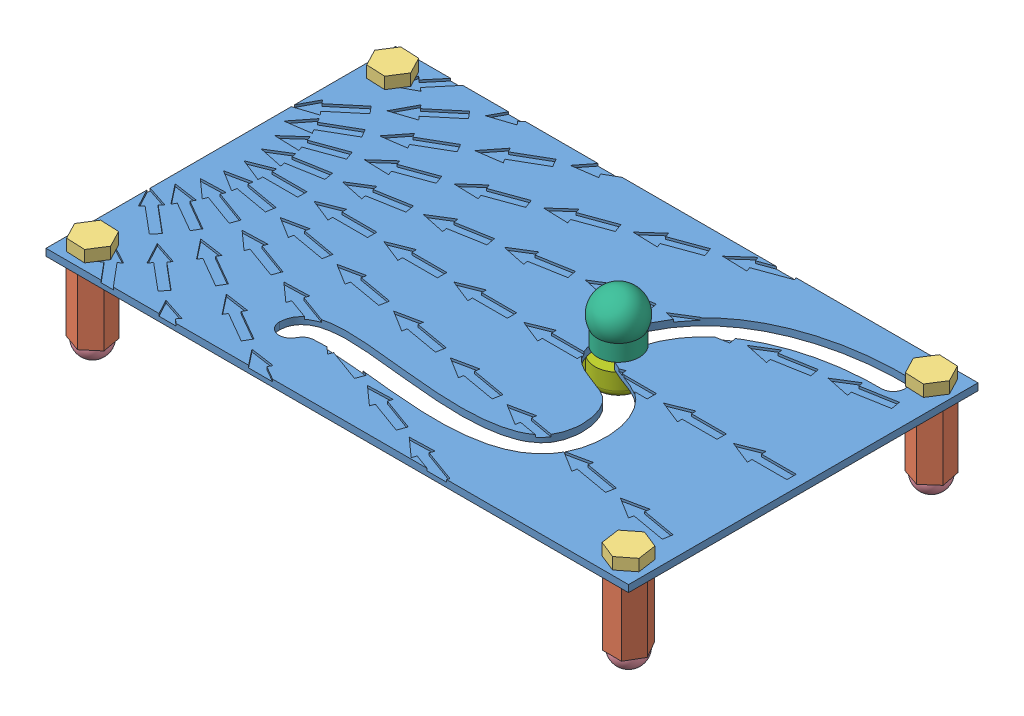
SolidWorks assembly line integral model 2, configuration Default. Lengths in mm.
Overall size (251.5 61.65 151.31).
16 component instances, 7 part files, 31 mates.
Components (placement in the parent):
- base3 - Copy-1: base3 - Copy [Default] at (17.0516 136.2086 235.579) size (250 3 150)
- washer-1: washer [Default] at (27.0516 106.2086 225.579) x (0.759078 0 -0.650999) z (0.650999 0 0.759078) size (16.17 30.96 14.03)
- washer-2: washer [Default] at (27.0516 106.2086 96.7735) size (16.17 30.96 14.03)
- washer-3: washer [Default] at (257.0516 106.2086 95.579) x (-0.748094 0 0.663593) z (-0.663593 0 -0.748094) size (16.17 30.96 14.03)
- washer-4: washer [Default] at (257.0516 106.2086 225.579) size (16.17 30.96 14.03)
- bolt-1: bolt [Default] at (27.0516 109.2086 96.7735) size (16.15 35.68 14.34)
- bolt-2: bolt [Default] at (27.0516 109.2086 225.579) size (16.15 35.68 14.34)
- bolt-3: bolt [Default] at (257.0516 109.2086 225.579) x (0.758823 0 -0.651297) z (0.651297 0 0.758823) size (16.15 35.68 14.34)
- bolt-4: bolt [Default] at (257.0516 109.2086 95.579) size (16.15 35.68 14.34)
- feet-1: feet [Default] at (257.0516 106.2086 95.579) x (-0.837169 0 -0.546944) z (-0.546944 0 0.837169) size (14 12.25 14)
- feet-2: feet [Default] at (27.0516 106.2086 225.579) x (-0.837169 0 -0.546944) z (-0.546944 0 0.837169) size (14 12.25 14)
- feet-3: feet [Default] at (27.0516 106.2086 96.7735) x (-0.837169 0 -0.546944) z (-0.546944 0 0.837169) size (14 12.25 14)
- feet-4: feet [Default] at (257.0516 106.2086 225.579) x (-0.837169 0 -0.546944) z (-0.546944 0 0.837169) size (14 12.25 14)
- band holder-1: band holder [Default] at (27.0516 126.2086 165.579) x (0 0 -1) z (1 0 0) size (10 10 10)
- slider - Copy-1: slider - Copy [Default] at (175.9335 127.2086 148.7713) x (-0.925693 0 -0.378276) z (0.378276 0 -0.925693) size (20.18 33.65 20.18)
- washer clip - Copy-1: washer clip - Copy [Default] at (175.9335 136.2086 148.7713) x (0.995786 0 -0.09171) z (-0.09171 0 -0.995786) size (29 10.27 20)
Mates (geometry in assembly coordinates):
- Coincident1: coincident anti-aligned: plane of base3 - Copy-1 through (17.0516 136.2086 235.579) normal (0 -1 0); plane of washer-1 through (27.0516 136.2086 225.579) normal (0 1 0)
- Coincident2: coincident anti-aligned: plane of base3 - Copy-1 through (17.0516 139.2086 235.579) normal (0 1 0); plane of bolt-2 through (27.0516 139.2086 225.579) normal (0 -1 0)
- Concentric1: concentric anti-aligned: cylinder of washer-1 through (27.0516 106.2086 225.579) axis (0 1 0) radius 5; cylinder of bolt-2 through (27.0516 139.2086 225.579) axis (0 -1 0) radius 5
- Concentric2: concentric anti-aligned: cylinder of base3 - Copy-1 through (27.0516 129.2086 225.579) axis (0 1 0) radius 1.5; cylinder of bolt-2 through (27.0516 139.2086 225.579) axis (0 -1 0) radius 5
- Coincident3: coincident anti-aligned: plane of base3 - Copy-1 through (17.0516 136.2086 235.579) normal (0 -1 0); plane of washer-2 through (27.0516 136.2086 96.7735) normal (0 1 0)
- Concentric3: concentric anti-aligned: cylinder of base3 - Copy-1 through (27.0516 129.2086 96.7735) axis (0 1 0) radius 1.5; cylinder of bolt-1 through (27.0516 139.2086 96.7735) axis (0 -1 0) radius 5
- Concentric4: concentric anti-aligned: cylinder of washer-2 through (27.0516 106.2086 96.7735) axis (0 1 0) radius 5; cylinder of bolt-1 through (27.0516 139.2086 96.7735) axis (0 -1 0) radius 5
- Coincident4: coincident anti-aligned: plane of base3 - Copy-1 through (17.0516 139.2086 235.579) normal (0 1 0); plane of bolt-1 through (27.0516 139.2086 96.7735) normal (0 -1 0)
- Coincident5: coincident anti-aligned: plane of base3 - Copy-1 through (17.0516 136.2086 235.579) normal (0 -1 0); plane of washer-4 through (257.0516 136.2086 225.579) normal (0 1 0)
- Concentric5: concentric anti-aligned: cylinder of base3 - Copy-1 through (257.0516 129.2086 225.579) axis (0 1 0) radius 1.5; cylinder of bolt-3 through (257.0516 139.2086 225.579) axis (0 -1 0) radius 5
- Coincident6: coincident anti-aligned: plane of base3 - Copy-1 through (17.0516 139.2086 235.579) normal (0 1 0); plane of bolt-3 through (257.0516 139.2086 225.579) normal (0 -1 0)
- Concentric6: concentric anti-aligned: cylinder of washer-4 through (257.0516 106.2086 225.579) axis (0 1 0) radius 5; cylinder of bolt-3 through (257.0516 139.2086 225.579) axis (0 -1 0) radius 5
- Coincident7: coincident anti-aligned: plane of base3 - Copy-1 through (17.0516 136.2086 235.579) normal (0 -1 0); plane of washer-3 through (257.0516 136.2086 95.579) normal (0 1 0)
- Coincident8: coincident anti-aligned: plane of base3 - Copy-1 through (17.0516 139.2086 235.579) normal (0 1 0); plane of bolt-4 through (257.0516 139.2086 95.579) normal (0 -1 0)
- Concentric7: concentric anti-aligned: cylinder of base3 - Copy-1 through (257.0516 129.2086 95.579) axis (0 1 0) radius 1.5; cylinder of bolt-4 through (257.0516 139.2086 95.579) axis (0 -1 0) radius 5
- Concentric8: concentric anti-aligned: cylinder of washer-3 through (257.0516 106.2086 95.579) axis (0 1 0) radius 5; cylinder of bolt-4 through (257.0516 139.2086 95.579) axis (0 -1 0) radius 5
- Coincident9: coincident anti-aligned: plane of washer-3 through (257.0516 106.2086 95.579) normal (0 -1 0); plane of feet-1 through (257.0516 106.2086 95.579) normal (0 1 0)
- Concentric9: concentric aligned: circle of washer-3; circle of feet-1
- Coincident10: coincident aligned: circle of washer-4; plane of feet-4 through (257.0516 106.2086 225.579) normal (0 1 0)
- Concentric10: concentric aligned: circle of washer-4; circle of feet-4
- Coincident11: coincident anti-aligned: plane of washer-1 through (27.0516 106.2086 225.579) normal (0 -1 0); plane of feet-2 through (27.0516 106.2086 225.579) normal (0 1 0)
- Concentric11: concentric aligned: circle of washer-1; circle of feet-2
- Coincident12: coincident anti-aligned: plane of washer-2 through (27.0516 106.2086 96.7735) normal (0 -1 0); plane of feet-3 through (27.0516 106.2086 96.7735) normal (0 1 0)
- Concentric12: concentric aligned: circle of washer-2; circle of feet-3
- Coincident13: coincident aligned: line of base3 - Copy-1 through (17.0516 136.2086 85.579) axis (0 0 1); line of band holder-1 through (17.0516 136.2086 155.579) axis (0 0 1)
- Coincident14: coincident anti-aligned: plane of base3 - Copy-1 through (17.0516 136.2086 235.579) normal (0 -1 0); plane of band holder-1 through (27.0516 136.2086 165.579) normal (0 1 0)
- Distance1: distance = 70 mm: line of band holder-1 through (27.0516 136.2086 155.579) axis (-1 0 0); line of base3 - Copy-1 through (267.0516 136.2086 85.579) axis (-1 0 0)
- Tangent6: tangent: face of base3 - Copy-1; cylinder of slider - Copy-1 through (175.9335 139.2086 148.7713) axis (0 -1 0) radius 4
- Coincident16: coincident anti-aligned: plane of base3 - Copy-1 through (17.0516 139.2086 235.579) normal (0 1 0); plane of slider - Copy-1 through (175.9335 139.2086 148.7713) normal (0 -1 0)
- Concentric13: concentric anti-aligned: cylinder of slider - Copy-1 through (175.9335 139.2086 148.7713) axis (0 -1 0) radius 4; cylinder of washer clip - Copy-1 through (175.9335 126.2086 148.7713) axis (0 1 0) radius 4
- Coincident17: coincident anti-aligned: plane of base3 - Copy-1 through (17.0516 136.2086 235.579) normal (0 -1 0); plane of washer clip - Copy-1 through (175.9335 136.2086 148.7713) normal (0 1 0)
